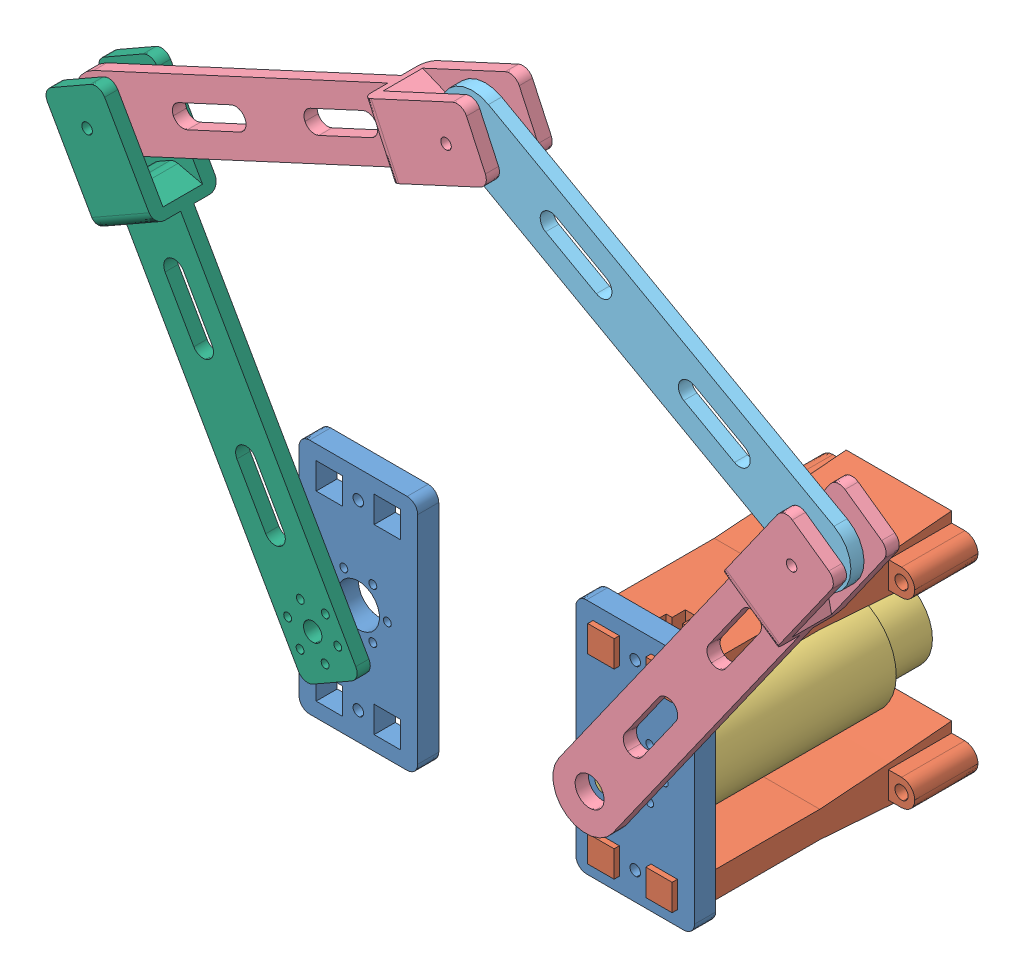
SolidWorks assembly Assem1, configuration Default. Lengths in mm.
Overall size (303.44 257.49 127.3).
9 component instances, 6 part files, 20 mates.
Components (placement in the parent):
- motor_base-1: motor_base [Default] at (37.0084 56.7498 56.6349) size (45 90 8)
- support-1: support [Default] at (37.0084 22.2498 10.6349) x (0 0 -1) z (0 1 0) size (102 60 18)
- support-2: support [Default] at (37.0084 91.2498 10.6349) x (0 0 -1) z (0 1 0) size (102 60 18)
- maxon_148877-1: maxon_148877 [Default] at (37.0084 56.7498 -14.3651) x (0.007063 0.999975 0) z (0.999975 -0.007063 0) size (40 110.03 45)
- handle2-1: handle2 [Varsayılan] at (68.6559 123.1647 79.4349) x (0 0 -1) z (0.816533 -0.577299 0) size (25 177.5 25)
- handle1-2: handle1 [Default] at (58.0859 215.733 76.9349) x (0.873564 -0.48671 0) z (0 0 1) size (175 25 5)
- motor_base-2: motor_base [Default] at (-67.9916 56.7498 56.6349) size (45 90 8)
- handle-2: handle [Varsayılan] at (-105.6047 97.4623 79.4349) x (0 0 -1) z (0.868627 0.495467 0) size (25 180 25)
- handle2-2: handle2 [Varsayılan] at (-83.0112 231.0187 79.4349) x (0 0 -1) z (0.420139 -0.90746 0) size (25 177.5 25)
Mates (geometry in assembly coordinates):
- Coincident8: coincident: plane of motor_base-1 through (55.5084 15.7498 56.6349) normal (0 0 -1); plane of support-2 through (37.0084 96.2498 56.6349) normal (0 0 1)
- Coincident9: coincident: plane of motor_base-1 through (55.5084 15.7498 56.6349) normal (0 0 -1); plane of support-1 through (37.0084 27.2498 56.6349) normal (0 0 1)
- Coincident10: coincident: plane of motor_base-1 through (53.0084 86.2498 64.6349) normal (0 1 0); plane of support-2 through (37.0084 86.2498 10.6349) normal (0 -1 0)
- Coincident11: coincident: plane of motor_base-1 through (43.0084 86.2498 64.6349) normal (1 0 0); plane of support-2 through (43.0084 96.2498 10.6349) normal (-1 0 0)
- Coincident12: coincident: plane of motor_base-1 through (53.0084 27.2498 64.6349) normal (0 -1 0); plane of support-1 through (37.0084 27.2498 10.6349) normal (0 1 0)
- Coincident13: coincident: plane of motor_base-1 through (53.0084 27.2498 64.6349) normal (-1 0 0); plane of support-1 through (53.0084 27.2498 10.6349) normal (1 0 0)
- Concentric1: concentric: circle of maxon_148877-1; circle of handle2-1
- Coincident14: coincident: plane of maxon_148877-1 through (37.0084 56.7498 76.9349) normal (0 0 1); plane of handle2-1 through (38.5556 37.2856 76.9349) normal (0 0 -1)
- Coincident15: coincident: plane of motor_base-1 through (55.5084 15.7498 56.6349) normal (0 0 -1); plane of maxon_148877-1 through (37.0084 56.7498 56.6349) normal (0 0 1)
- Concentric2: concentric: circle of motor_base-1; circle of maxon_148877-1
- Concentric4: concentric: circle of handle2-1; circle of handle1-2
- Distance2: distance = 5 mm: plane of handle1-2 through (-7.4313 252.2362 76.9349) normal (0 0 -1); plane of handle2-1 through (123.1299 156.9077 71.9349) normal (0 0 1)
- Coincident16: coincident: plane of motor_base-1 through (55.5084 101.7498 64.6349) normal (0 1 0); plane of motor_base-2 through (-49.4916 101.7498 64.6349) normal (0 1 0)
- Distance3: distance = 60 mm: plane of motor_base-1 through (14.5084 15.7498 64.6349) normal (-1 0 0); plane of motor_base-2 through (-45.4916 15.7498 64.6349) normal (1 0 0)
- Coincident17: coincident: plane of motor_base-1 through (55.5084 15.7498 64.6349) normal (0 0 1); plane of motor_base-2 through (-49.4916 15.7498 64.6349) normal (0 0 1)
- Concentric5: concentric: circle of motor_base-2; circle of handle-2
- Concentric6: concentric: circle of handle-2; circle of handle2-2
- Distance4: distance = 5 mm: plane of handle-2 through (-138.8858 206.2666 86.9349) normal (0 0 -1); plane of handle2-2 through (-151.9105 171.5701 81.9349) normal (0 0 1)
- Concentric7: concentric: circle of handle1-2; circle of handle2-2
- Distance5: distance = 5 mm: plane of handle2-2 through (9.1636 246.1447 86.9349) normal (0 0 -1); plane of handle1-2 through (-7.4313 252.2362 81.9349) normal (0 0 1)
